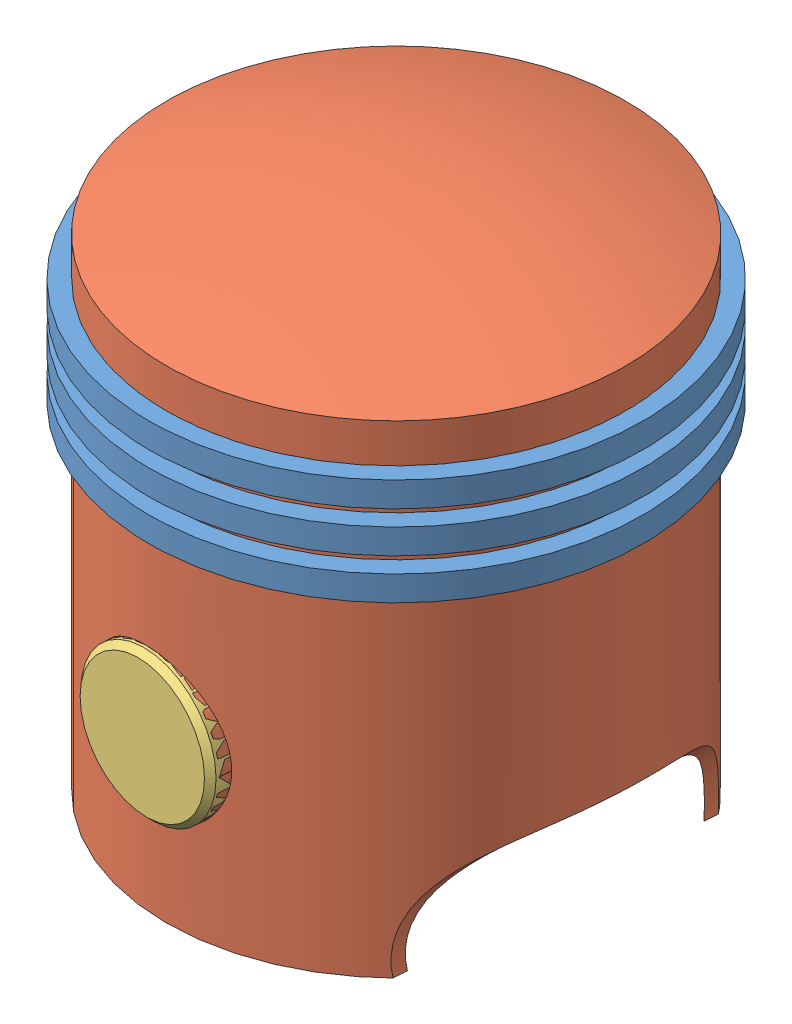
SolidWorks assembly PISTON WITH RING AND PIN, configuration Default. Lengths in mm.
Overall size (85 91.79 85).
5 component instances, 3 part files, 8 mates.
Components (placement in the parent):
- assembly piston ring-1: assembly piston ring [Default] at (-1.1571 50.7228 76.8129) size (85 4.3 85)
- piston assembly-1: piston assembly [Default] at (-1.1571 -7.2772 76.8129) x (0.997722 0 0.067454) z (-0.067454 0 0.997722) size (79 91.79 79)
- assembly piston ring-2: assembly piston ring [Default] at (-1.1571 64.7228 76.8129) size (85 4.3 85)
- assembly piston ring-3: assembly piston ring [Default] at (-1.1571 57.7228 76.8129) size (85 4.3 85)
- assembly piston pin-1: assembly piston pin [Default] at (1.6085 19.7228 35.9063) x (0.959077 0.275621 0.064841) z (0.274993 -0.961266 0.018592) size (25 82 25)
Mates (geometry in assembly coordinates):
- Concentric1: concentric anti-aligned: cylinder of piston assembly-1 through (-1.1571 75.7228 76.8129) axis (0 1 0) radius 37.5; cylinder of assembly piston ring-2 through (-1.1571 69.0228 76.8129) axis (0 -1 0) radius 39.5
- Coincident1: coincident anti-aligned: plane of piston assembly-1 through (-42.5626 64.7228 74.0135) normal (0 1 0); plane of assembly piston ring-2 through (-1.1571 64.7228 76.8129) normal (0 -1 0)
- Concentric2: concentric anti-aligned: cylinder of piston assembly-1 through (-1.1571 75.7228 76.8129) axis (0 1 0) radius 37.5; cylinder of assembly piston ring-3 through (-1.1571 62.0228 76.8129) axis (0 -1 0) radius 39.5
- Coincident2: coincident anti-aligned: plane of piston assembly-1 through (-42.5626 57.7228 74.0135) normal (0 1 0); plane of assembly piston ring-3 through (-1.1571 57.7228 76.8129) normal (0 -1 0)
- Concentric3: concentric anti-aligned: cylinder of assembly piston ring-1 through (-1.1571 55.0228 76.8129) axis (0 -1 0) radius 39.5; cylinder of piston assembly-1 through (-1.1571 75.7228 76.8129) axis (0 1 0) radius 37.5
- Coincident3: coincident anti-aligned: plane of assembly piston ring-1 through (-1.1571 50.7228 76.8129) normal (0 -1 0); plane of piston assembly-1 through (-42.5626 50.7228 74.0135) normal (0 1 0)
- Concentric4: concentric anti-aligned: cylinder of piston assembly-1 through (1.5074 19.7228 37.4018) axis (-0.067454 0 0.997722) radius 10; cylinder of assembly piston pin-1 through (-3.9227 19.7228 117.7195) axis (0.067454 0 -0.997722) radius 12.5
- Width1: width anti-aligned: plane of assembly piston pin-1 through (1.6085 19.7228 35.9063) normal (0.067454 0 -0.997722); plane of piston assembly-1 through (-3.9227 19.7228 117.7195) normal (-0.067454 0 0.997722); plane of assembly piston pin-1 through (-3.8216 19.7228 116.2229) normal (-0.067454 0 0.997722); plane of piston assembly-1 through (1.5073 19.7228 37.4028) normal (0.067454 0 -0.997722)
